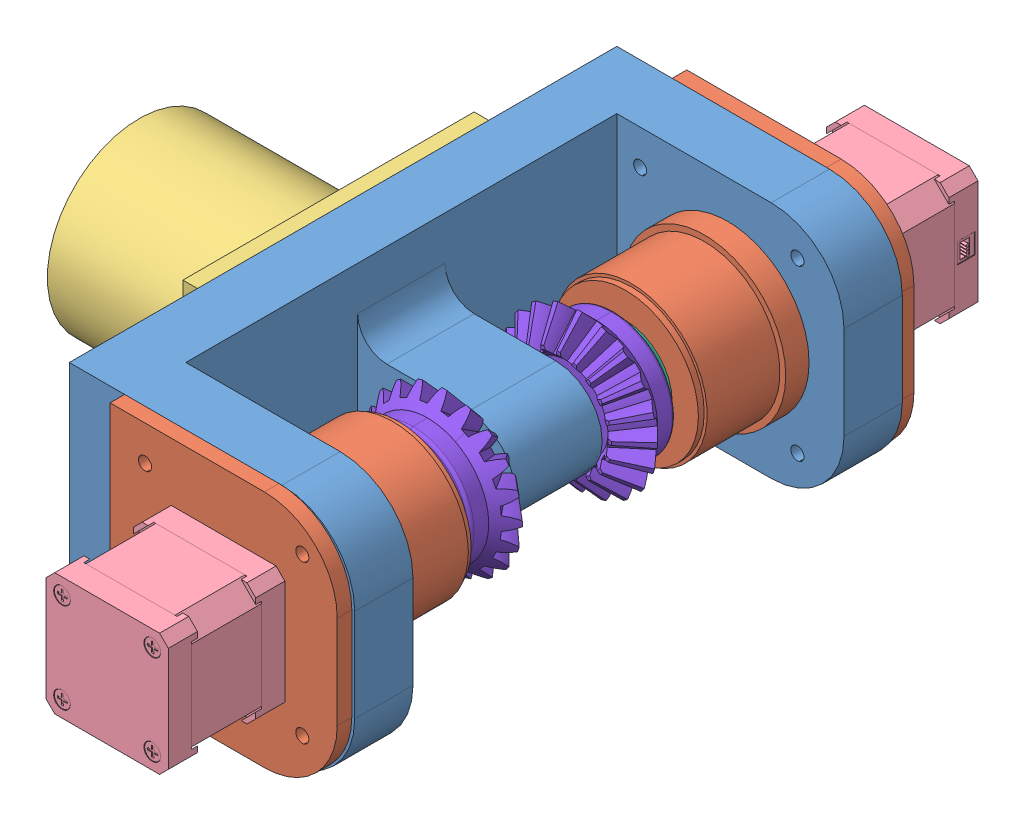
SolidWorks assembly Wrist assembly v2, configuration Default. Lengths in mm.
Overall size (168 82 278).
16 component instances, 9 part files, 41 mates.
Components (placement in the parent):
- Wrist input frame-1: Wrist input frame [Default] at (11.8915 95.9253 67.0207) x (0 0 1) z (0 1 0) size (188 98 82)
- Motor sleeve-1: Motor sleeve [Default] at (69.8915 54.9253 -26.9793) x (0 0 1) z (-1 0 0) size (60 82 78)
- Motor sleeve-2: Motor sleeve [Default] at (69.8915 54.9253 161.0207) x (0 0 -1) z (-1 0 0) size (60 82 78)
- Wrist mount-2: Wrist mount [Default] at (11.8915 54.9253 67.0207) x (0 0 1) z (-1 0 0) size (100 82 80)
- 17HS15-1684D-HG10-AR3-1: 17HS15-1684D-HG10-AR3 [Default] at (69.8915 54.9253 -31.9793) size (42.88 42 103.5)
- 17HS15-1684D-HG10-AR3-2: 17HS15-1684D-HG10-AR3 [Default] at (69.8915 54.9253 166.0207) x (-1 0 0) z (0 0 -1) size (42.88 42 103.5)
- WGB1498954-1: WGB1498954 [Default] at (69.8915 54.9253 69.0207) x (0.98669 -0.162615 0) z (0 0 1) size (22 22 13)
- WGB1498954-2: WGB1498954 [Default] at (69.8915 54.9253 52.0207) x (0.931267 0.364339 0) z (0 0 1) size (22 22 13)
- WWG35HY95-1: WWG35HY95 [Default] at (69.8915 54.9253 12.0207) x (0.560366 -0.828245 0) z (0 0 1) size (32 32 15.9)
- WWG35HY95-2: WWG35HY95 [Default] at (69.8915 54.9253 106.1207) x (0.452091 -0.891972 0) z (0 0 1) size (32 32 15.9)
- shaft-1: shaft [Default] at (69.8915 54.9253 63.9207) x (-1 0 0) z (0 0 -1) size (15 15 55)
- shaft-2: shaft [Default] at (69.8915 54.9253 70.1207) size (15 15 55)
- A 1C 4MYKW25020-1: A 1C 4MYKW25020 [Default] at (69.8915 54.9253 67.0207) x (-1 0 0) z (0 -1 0) size (54.54 19 54.54)
- A 1C 4MYKW25020-2: A 1C 4MYKW25020 [Default] at (69.8915 54.9253 67.0207) x (1 0 0) z (0 -1 0) size (54.54 19 54.54)
- spacer-1: spacer [Default] at (69.8915 54.9253 102.0207) x (-0.432652 -0.901561 0) z (0 0 1) size (25 25 2.1)
- spacer-2: spacer [Default] at (69.8915 54.9253 29.9207) x (-0.432652 -0.901561 0) z (0 0 1) size (25 25 2.1)
Mates (geometry in assembly coordinates):
- Concentric2: concentric anti-aligned: circle of Wrist input frame-1; circle of Motor sleeve-1
- Parallel2: parallel aligned: plane of Wrist input frame-1 through (11.8915 13.9253 67.0207) normal (-1 0 0); plane of Motor sleeve-1 through (30.8915 13.9253 -31.9793) normal (-1 0 0)
- Coincident3: coincident anti-aligned: plane of Wrist input frame-1 through (11.8915 13.9253 -26.9793) normal (0 0 -1); plane of Motor sleeve-1 through (69.8915 54.9253 -26.9793) normal (0 0 1)
- Parallel3: parallel aligned: plane of Wrist input frame-1 through (11.8915 13.9253 67.0207) normal (-1 0 0); plane of Motor sleeve-2 through (30.8915 95.9253 166.0207) normal (-1 0 0)
- Coincident4: coincident anti-aligned: plane of Wrist input frame-1 through (11.8915 13.9253 161.0207) normal (0 0 1); plane of Motor sleeve-2 through (69.8915 54.9253 161.0207) normal (0 0 -1)
- Concentric4: concentric aligned: circle of Wrist input frame-1; circle of Wrist mount-2
- Parallel4: parallel aligned: plane of Wrist input frame-1 through (11.8915 95.9253 67.0207) normal (0 1 0); plane of Wrist mount-2 through (6.8915 95.9253 17.0207) normal (0 1 0)
- Coincident5: coincident anti-aligned: plane of Wrist input frame-1 through (11.8915 13.9253 67.0207) normal (-1 0 0); plane of Wrist mount-2 through (11.8915 54.9253 67.0207) normal (1 0 0)
- Parallel5: parallel anti-aligned: plane of Wrist input frame-1 through (11.8915 13.9253 67.0207) normal (0 -1 0)
- Parallel6: parallel aligned: plane of Wrist input frame-1 through (11.8915 95.9253 67.0207) normal (1 0 0)
- Concentric5: concentric anti-aligned: circle of Motor sleeve-1; circle of 17HS15-1684D-HG10-AR3-1
- Parallel7: parallel aligned: plane of Wrist input frame-1 through (11.8915 95.9253 67.0207) normal (0 1 0); plane of 17HS15-1684D-HG10-AR3-1 through (69.8915 75.9253 -123.3763) normal (0 1 0)
- Coincident6: coincident anti-aligned: plane of Motor sleeve-1 through (69.8915 75.9253 8.0207) normal (0 0 -1); plane of 17HS15-1684D-HG10-AR3-1 through (69.8915 54.9253 8.0207) normal (0 0 1)
- Concentric6: concentric anti-aligned: cylinder of Motor sleeve-2 through (69.8915 54.9253 225.124) axis (0 0 1) radius 21; circle of 17HS15-1684D-HG10-AR3-2
- Parallel8: parallel aligned: plane of Wrist input frame-1 through (11.8915 95.9253 67.0207) normal (0 1 0); plane of 17HS15-1684D-HG10-AR3-2 through (69.8915 75.9253 257.4177) normal (0 1 0)
- Coincident8: coincident anti-aligned: plane of Motor sleeve-2 through (69.8915 33.9253 126.0207) normal (0 0 1); plane of 17HS15-1684D-HG10-AR3-2 through (69.8915 54.9253 126.0207) normal (0 0 -1)
- Concentric7: concentric anti-aligned: circle of Wrist input frame-1; circle of WGB1498954-1
- Coincident9: coincident anti-aligned: plane of Wrist input frame-1 through (69.8915 54.9253 69.0207) normal (0 0 1); circle of WGB1498954-1
- Concentric8: concentric anti-aligned: circle of Wrist input frame-1; circle of WGB1498954-2
- Coincident10: coincident anti-aligned: plane of Wrist input frame-1 through (69.8915 54.9253 65.0207) normal (0 0 -1); circle of WGB1498954-2
- Concentric9: concentric anti-aligned: circle of Motor sleeve-1; circle of WWG35HY95-1
- Coincident11: coincident anti-aligned: plane of Motor sleeve-1 through (69.8915 69.9253 12.0207) normal (0 0 1); circle of WWG35HY95-1
- Concentric10: concentric anti-aligned: circle of 17HS15-1684D-HG10-AR3-2; circle of WWG35HY95-2
- Coincident12: coincident anti-aligned: plane of Motor sleeve-2 through (69.8915 39.9253 122.0207) normal (0 0 -1); circle of WWG35HY95-2
- Concentric11: concentric anti-aligned: circle of Wrist input frame-1; circle of Motor sleeve-2
- Parallel9: parallel aligned: plane of 17HS15-1684D-HG10-AR3-1 through (68.3915 55.9253 27.4207) normal (1 0 0); plane of shaft-1 through (68.3915 47.4243 16.4207) normal (1 0 0)
- Concentric12: concentric anti-aligned: circle of 17HS15-1684D-HG10-AR3-1; circle of shaft-1
- Coincident13: coincident anti-aligned: plane of WWG35HY95-1 through (69.8915 54.9253 27.9207) normal (0 0 1); circle of shaft-1
- Parallel10: parallel aligned: plane of 17HS15-1684D-HG10-AR3-2 through (68.3915 55.9253 106.6207) normal (1 0 0); plane of shaft-2 through (68.3915 47.4243 117.6207) normal (1 0 0)
- Concentric13: concentric anti-aligned: circle of 17HS15-1684D-HG10-AR3-2; circle of shaft-2
- Coincident14: coincident anti-aligned: plane of WWG35HY95-2 through (69.8915 54.9253 106.1207) normal (0 0 -1); circle of shaft-2
- Concentric14: concentric aligned: cylinder of shaft-2 through (69.8915 54.9253 104.1207) axis (0 0 -1) radius 7; circle of A 1C 4MYKW25020-1
- Distance1: distance = 2.1 mm anti-aligned: plane of shaft-2 through (69.8915 54.9253 104.1207) normal (0 0 -1); plane of A 1C 4MYKW25020-1 through (69.8915 54.9253 102.0207) normal (0 0 1)
- Concentric15: concentric aligned: cylinder of shaft-1 through (69.8915 54.9253 29.9207) axis (0 0 1) radius 7; circle of A 1C 4MYKW25020-2
- Distance2: distance = 2.1 mm anti-aligned: plane of shaft-1 through (69.8915 54.9253 29.9207) normal (0 0 1); plane of A 1C 4MYKW25020-2 through (69.8915 54.9253 32.0207) normal (0 0 -1)
- Parallel11: parallel aligned: plane of shaft-1 through (67.3915 59.6253 51.0207) normal (1 0 0); plane of A 1C 4MYKW25020-2 through (67.3915 64.2253 57.5207) normal (1 0 0)
- Parallel12: parallel aligned: plane of shaft-2 through (67.3915 59.6253 83.0207) normal (1 0 0); plane of A 1C 4MYKW25020-1 through (67.3915 54.9253 76.5207) normal (1 0 0)
- Coincident15: coincident aligned: plane of A 1C 4MYKW25020-1 through (69.8915 54.9253 102.0207) normal (0 0 1); circle of spacer-1
- Concentric16: concentric aligned: cylinder of A 1C 4MYKW25020-1 through (69.8915 54.9253 115.0207) axis (0 0 1) radius 21; circle of spacer-1
- Coincident16: coincident anti-aligned: plane of A 1C 4MYKW25020-2 through (69.8915 54.9253 32.0207) normal (0 0 -1); circle of spacer-2
- Concentric17: concentric anti-aligned: cylinder of A 1C 4MYKW25020-2 through (69.8915 54.9253 19.0207) axis (0 0 -1) radius 21; circle of spacer-2
